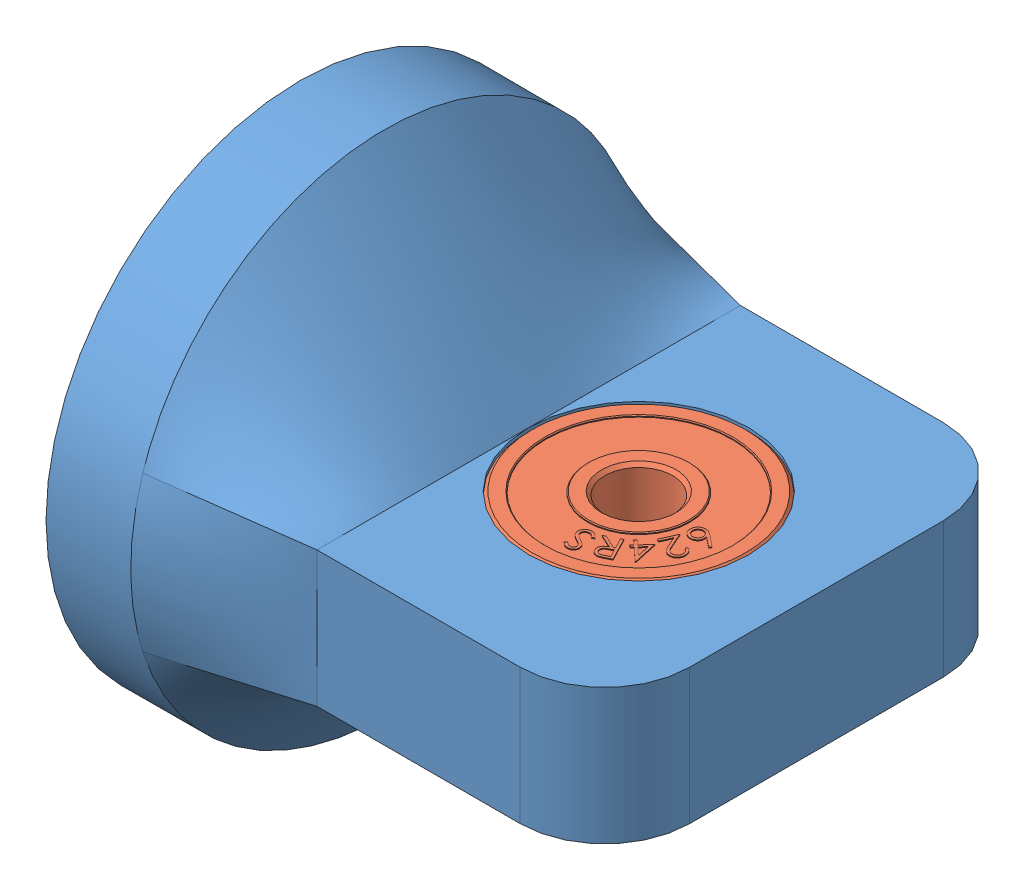
SolidWorks assembly doublebearing, configuration Default. Lengths in mm.
Overall size (30.5 30.1 30.39).
3 component instances, 2 part files, 4 mates.
Components (placement in the parent):
- double-bearing-1: double-bearing [Default] at (9.8834 5.4269 25.7772) size (30.5 30.1 30.39)
- 624RS-1: 624RS [Default] at (4.8834 5.4269 25.7772) x (0 0 -1) z (1 0 0) size (13 13 5)
- 624RS-2: 624RS [Default] at (24.8834 9.4269 25.7772) x (0 0 -1) z (0 -1 0) size (13 13 5)
Mates (geometry in assembly coordinates):
- Concentric1: concentric anti-aligned: circle of double-bearing-1; circle of 624RS-1
- Coincident2: coincident aligned: plane of double-bearing-1 through (4.8834 5.4269 25.7772) normal (-1 0 0); plane of 624RS-1 through (4.8834 5.4269 25.7772) normal (-1 0 0)
- Concentric2: concentric anti-aligned: cylinder of double-bearing-1 through (24.8834 9.4269 25.7772) axis (0 -1 0) radius 6.5; cylinder of 624RS-2 through (24.8834 4.4269 25.7772) axis (0 1 0) radius 6.5
- Coincident3: coincident aligned: plane of double-bearing-1 through (35.3834 9.4269 38.2772) normal (0 1 0); plane of 624RS-2 through (24.8834 9.4269 25.7772) normal (0 1 0)
